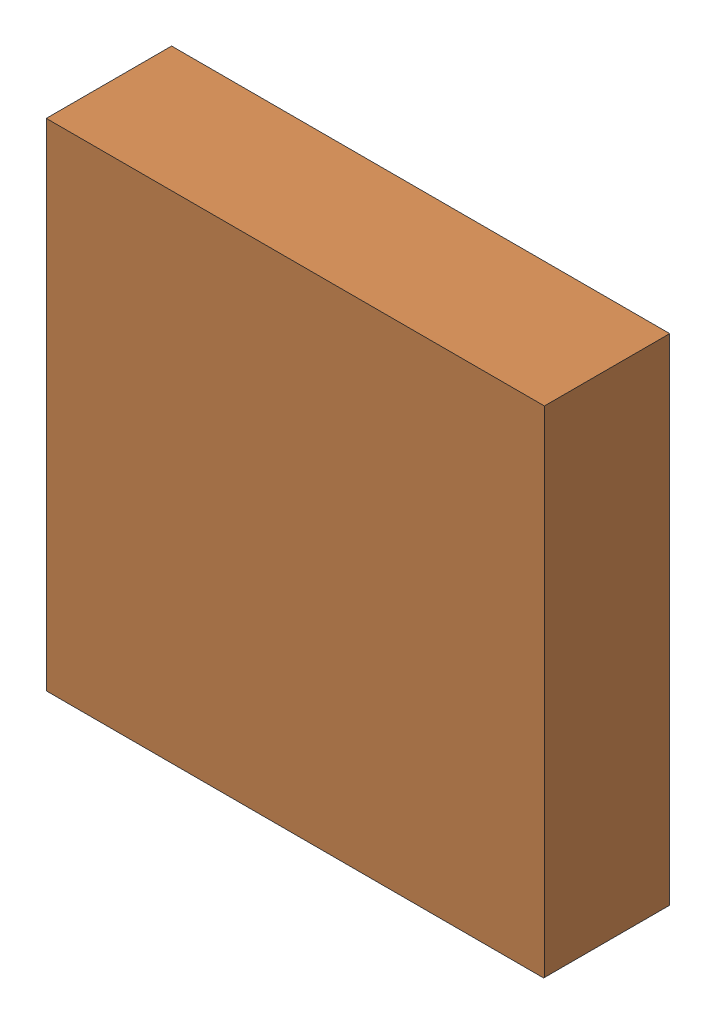
SolidWorks assembly U3, configuration ﾃﾞﾌｫﾙﾄ. Lengths in mm.
Overall size (3.19 3.17 0.82).
4 component instances, 2 part files, 0 mates.
Components (placement in the parent):
- 6641441328-1: 6641441328 [ﾃﾞﾌｫﾙﾄ] at (12.1608 18.3998 -2.7339) x (-1 0 0) z (0 0 -1) size (0.2 0.2 0.01)
  - Cylinder-22-1: Cylinder-22 [ﾃﾞﾌｫﾙﾄ] at origin size (0.2 0.2 0.01)
- 6641441568-1: 6641441568 [ﾃﾞﾌｫﾙﾄ] at (10.9 17.0875 -2.7339) size (3.19 3.17 0.81)
  - Extruded-21-1: Extruded-21 [ﾃﾞﾌｫﾙﾄ] at origin size (3.19 3.17 0.81)
